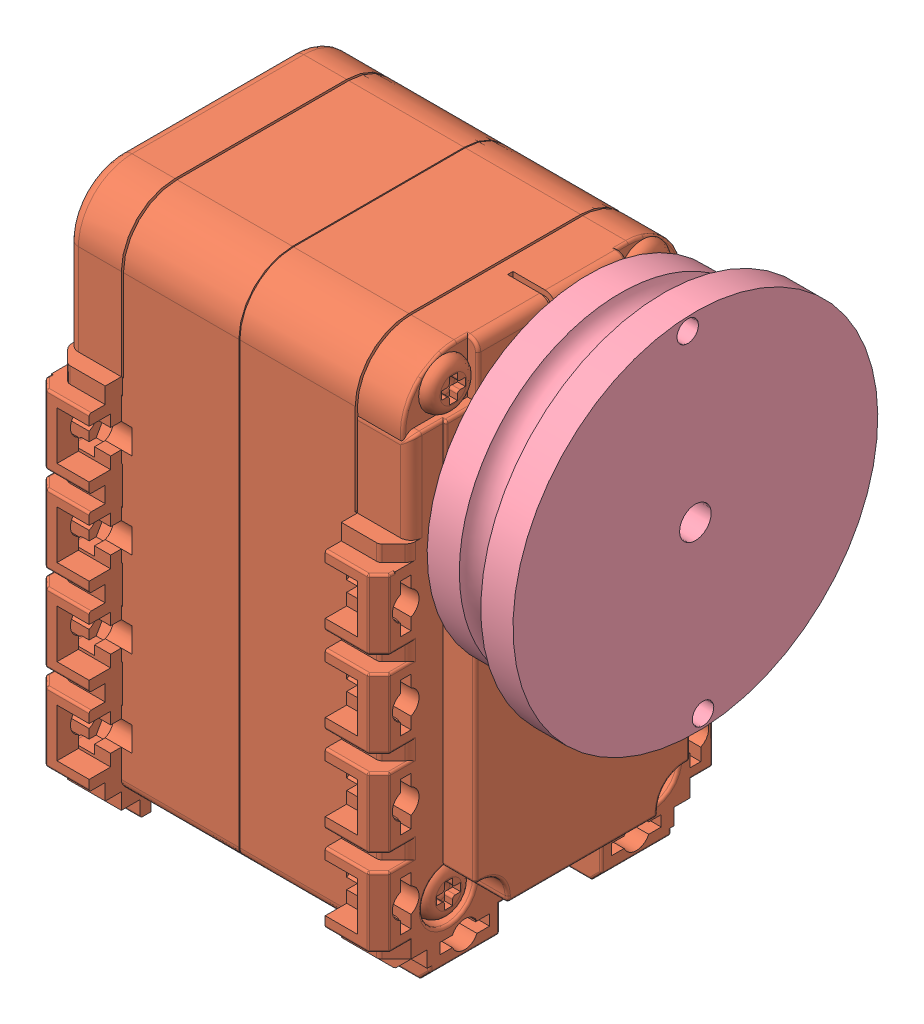
SolidWorks assembly AX12, configuration Default. Lengths in mm.
Overall size (48.5 56.25 35.5).
4 component instances, 4 part files, 5 mates.
Components (placement in the parent):
- ax12_wheel-1: ax12_wheel [Default] at (35.6652 29.55 -1.771) x (0 0.99898 0.045152) z (0 0.045152 -0.99898) size (22 14.85 22)
- ax12_box-1: ax12_box [Default] at (16.6652 17.55 -1.771) x (0 -1 0) z (0 0 -1) size (50 38.01 32)
- ax12_cog-1: ax12_cog [Default] at origin size (1 1 1)
- servoPulleyRX28-1: servoPulleyRX28 [Default] at (43.1652 29.55 -1.771) x (0 -0.99898 -0.045152) z (-1 0 0) size (34 34 10)
Mates (geometry in assembly coordinates):
- Concentric1: concentric: cylinder of ax12_wheel-1 through (27.6652 37.5418 -1.4098) axis (1 0 0) radius 1.25; cylinder of servoPulleyRX28-1 through (38.6652 37.5418 -1.4098) axis (1 0 0) radius 2.3
- Concentric2: concentric: cylinder of ax12_wheel-1 through (27.6652 29.9112 -9.7629) axis (1 0 0) radius 1.25; cylinder of servoPulleyRX28-1 through (38.6652 29.9112 -9.7629) axis (1 0 0) radius 2.3
- Distance1: distance = 1.5 mm anti-aligned: plane of ax12_wheel-1 through (37.6652 29.55 -1.771) normal (1 0 0); plane of servoPulleyRX28-1 through (39.1652 29.55 -1.771) normal (-1 0 0)
- Concentric3: concentric aligned: cylinder of ax12_wheel-1 through (23.6652 29.55 -1.771) axis (1 0 0) radius 3; cylinder of ax12_box-1 through (23.6652 29.55 -1.771) axis (1 0 0) radius 3
- Coincident2: coincident anti-aligned: plane of ax12_wheel-1 through (33.6652 29.55 -1.771) normal (-1 0 0); plane of ax12_box-1 through (33.6652 29.55 -1.771) normal (1 0 0)
